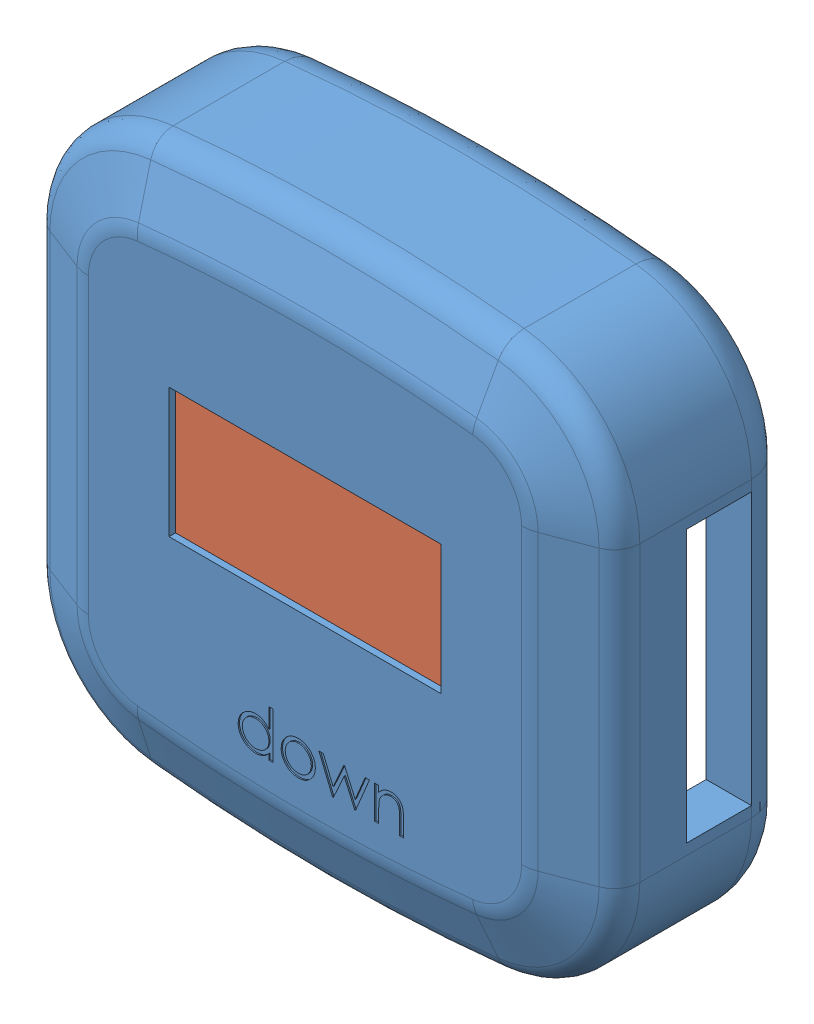
SolidWorks assembly EspruinoWatch, configuration Défaut. Lengths in mm.
Overall size (45 44 15.6).
4 component instances, 4 part files, 5 mates.
Components (placement in the parent):
- bracelet-2: bracelet [Défaut] at origin
- case-2: case [Défaut] at (27.7631 2.8863 25.2449) size (45 44 15)
- display-2: display [Défaut] at (21.8198 0.6006 35.4449) size (28 28 4.3)
- puck-1: puck [Défaut] at (28.5934 -2.3107 31.4449) size (29 29 10.8)
Mates (geometry in assembly coordinates):
- Parallèle2: parallel aligned: plane of case-2 through (37.3853 13.786 40.2449) normal (0 0 1); plane of display-2 through (21.8198 0.6006 39.7449) normal (0 0 1)
- Parallèle3: parallel anti-aligned: plane of case-2 through (9.8853 -12.5475 37.2449) normal (1 0 0); plane of display-2 through (11.5353 11.9845 39.4449) normal (-1 0 0)
- Coïncidente4: coincident: point of case-2; point of display-2
- Coïncidente5: coincident anti-aligned: plane of display-2 through (21.8198 0.6006 35.4449) normal (0 0 -1); plane of puck-1 through (28.5934 -2.3107 35.4449) normal (0 0 1)
- Coïncidente9: coincident: point of puck-1; line of assembly
